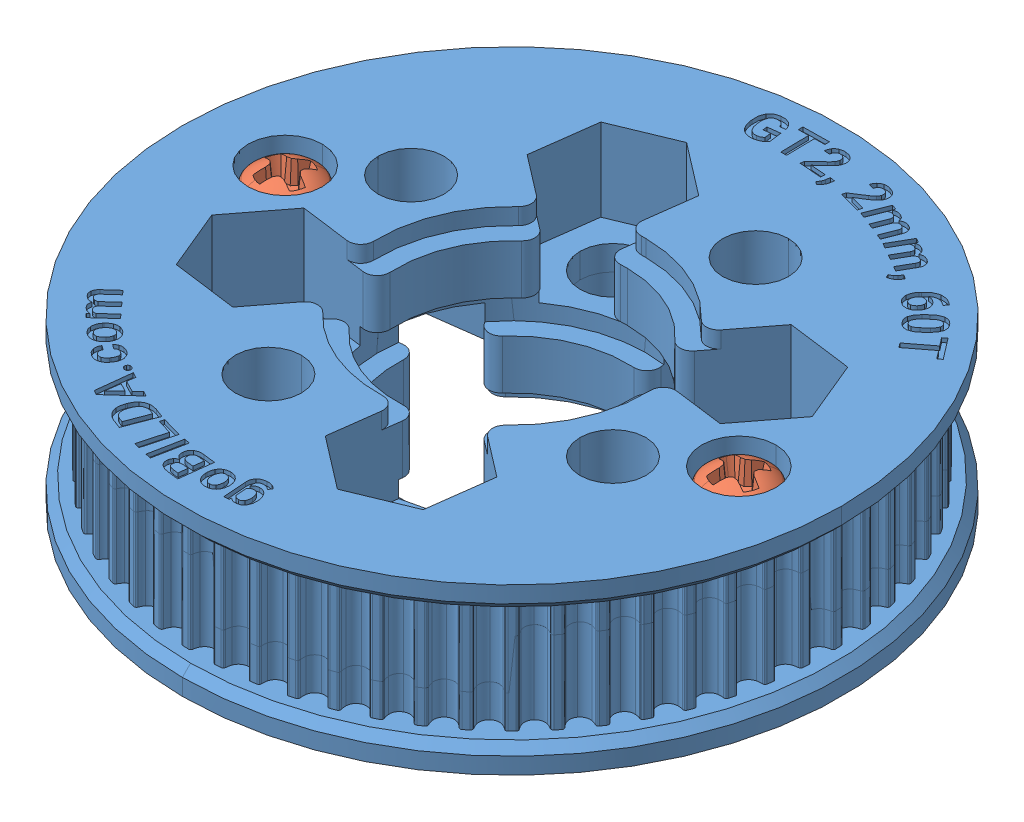
SolidWorks assembly 2mm Pitch GT2 Hub-Mount Timing Belt Pulley 3421-0014-0060 assembly.STEP, configuration Default. Lengths in mm.
Overall size (40 10.63 40).
6 component instances, 2 part files, 0 mates.
Components (placement in the parent):
- 3421-0014-0060.STEP-1: 3421-0014-0060.STEP [Default] at (-38.7161 5.2207 18.072) size (40 6.5 40)
- 3421-0014-0060.STEP-2: 3421-0014-0060.STEP [Default] at (-38.7161 5.2207 18.072) x (0 0 -1) z (-1 0 0) size (40 6.5 40)
- 3421-0014-0060 screw.STEP-1: 3421-0014-0060 screw.STEP [Default] at (-53.5007 8.5207 17.0492) x (0.927017 0 0.375019) z (0 1 0) size (4.27 4 8.02)
- 3421-0014-0060 screw.STEP-2: 3421-0014-0060 screw.STEP [Default] at (-23.9314 8.5207 19.0947) x (-0.927017 0 -0.375019) z (0 1 0) size (4.27 4 8.02)
- 3421-0014-0060 screw.STEP-3: 3421-0014-0060 screw.STEP [Default] at (-37.6933 1.9207 32.8566) x (-0.131756 0 -0.991282) z (0 -1 0) size (4.27 4 8.02)
- 3421-0014-0060 screw.STEP-4: 3421-0014-0060 screw.STEP [Default] at (-39.7388 1.9207 3.2873) x (0.131756 0 0.991282) z (0 -1 0) size (4.27 4 8.02)
